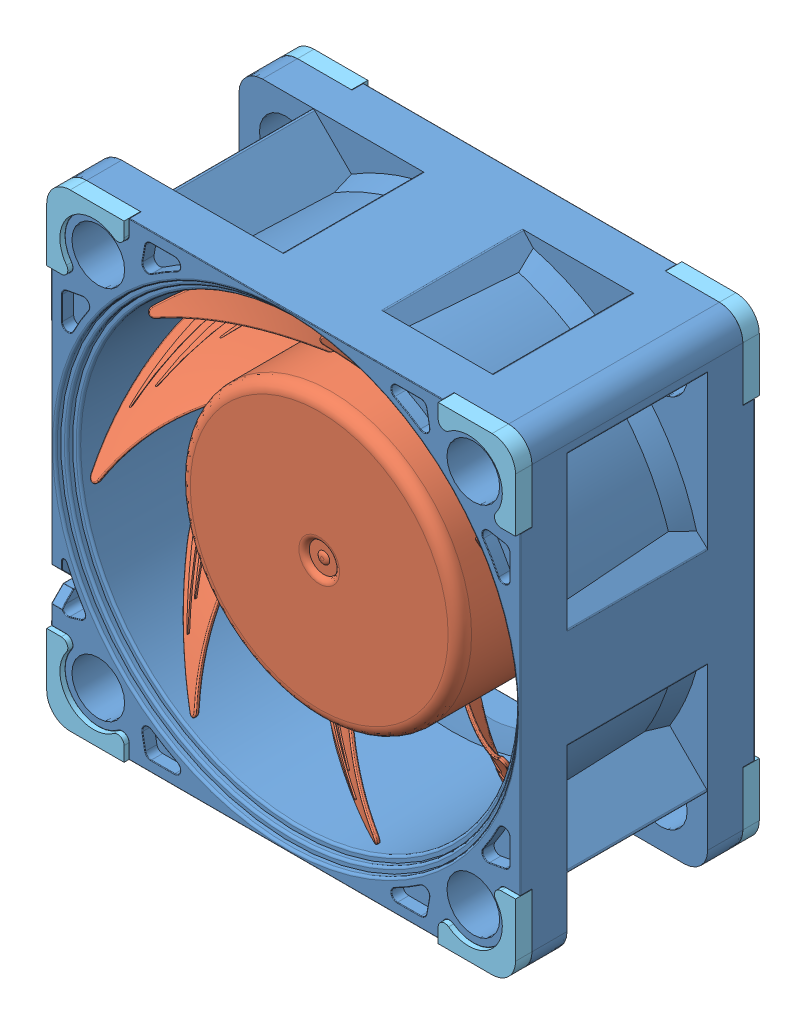
SolidWorks assembly NF-A4x20, configuration Predeterminado. Lengths in mm.
Overall size (49.24 49.24 20.8).
33 component instances, 18 part files, 22 mates.
Components (placement in the parent):
- Case20-1: Case20 [Predeterminado] at origin size (40 40 20.31)
- Impeller20-1: Impeller20 [Predeterminado] at (0 0 5.65) x (-0.910833 -0.412774 0) z (0 0 1) size (37.2 37.2 13.1)
- Magnet 20-1: Magnet 20 [Predeterminado] at (0 0 0.35) size (2 2 1.8)
- Back plate 20-1: Back plate 20 [Predeterminado] at (0 0 -0.05) size (19.4 19.4 0.4)
- Silent block-1: Silent block [Predeterminado] at (-16 16 -0.4) size (6.6 6.6 1.4)
- Silent block-2: Silent block [Predeterminado] at (-16 16 19) size (6.6 6.6 1.4)
- Silent block-3: Silent block [Predeterminado] at (16 16 -0.4) x (0 -1 0) z (0 0 1) size (6.6 6.6 1.4)
- Silent block-4: Silent block [Predeterminado] at (16 -16 -0.4) x (-1 0 0) z (0 0 1) size (6.6 6.6 1.4)
- Silent block-5: Silent block [Predeterminado] at (-16 -16 -0.4) x (0 1 0) z (0 0 1) size (6.6 6.6 1.4)
- Silent block-6: Silent block [Predeterminado] at (16 16 19) x (0 -1 0) z (0 0 1) size (6.6 6.6 1.4)
- Silent block-7: Silent block [Predeterminado] at (16 -16 19) x (-1 0 0) z (0 0 1) size (6.6 6.6 1.4)
- Silent block-8: Silent block [Predeterminado] at (-16 -16 19) x (0 1 0) z (0 0 1) size (6.6 6.6 1.4)
- Brushless motor-1: Brushless motor [Predeterminado] at (0 0 4) x (0.568712 -0.822537 0) z (0 0 1) size (16 16 8.48)
  - Board-1: Board [Predeterminado] at origin size (16 16 0.8)
  - Stator-1: Stator [Predeterminado] at (0 0 3.55) size (11.93 12 5.5)
  - Hall Effect sensor-1: Hall Effect sensor [WE] at (-5.3023 -0.9391 0) x (-0.233503 0.972356 0) z (-0.972356 -0.233503 0) size (6.3 1.6 2.6)
  - Controller-1: Controller [Predeterminado] at (5.1574 2.3195 0) x (0.319288 -0.947658 0) z (0.947658 0.319288 0) size (4.81 0.99 3)
  - Coil-1: Coil [Predeterminado] at (0 -5.01 1.29) x (-1 0 0) z (0 1 0) size (2.38 5.38 1.58)
  - Coil-2: Coil [Predeterminado] at (-4.3388 -2.505 1.29) x (-0.5 0.866025 0) z (0.866025 0.5 0) size (2.38 5.38 1.58)
  - Coil-3: Coil [Predeterminado] at (-4.3388 2.505 1.29) x (0.5 0.866025 0) z (0.866025 -0.5 0) size (2.38 5.38 1.58)
  - Coil-4: Coil [Predeterminado] at (0 5.01 1.29) x (1 0 0) z (0 -1 0) size (2.38 5.38 1.58)
  - Coil-5: Coil [Predeterminado] at (4.3388 2.505 1.29) x (0.5 -0.866025 0) z (-0.866025 -0.5 0) size (2.38 5.38 1.58)
  - Coil-6: Coil [Predeterminado] at (4.3388 -2.505 1.29) x (-0.5 -0.866025 0) z (-0.866025 0.5 0) size (2.38 5.38 1.58)
  - Pieza2^Brushless motor-1: Pieza2^Brushless motor [Predeterminado] at origin size (10.72 12.51 6.88) (virtual)
  - Pieza3^Brushless motor-1: Pieza3^Brushless motor [Predeterminado] at (0 0 0.8) size (4.1 0.74 1.7) (virtual)
- Shaft-1: Shaft [Predeterminado] at (0 0 16.35) x (0.952278 -0.305233 0) z (0 0 1) size (2.38 2.38 12.5)
- Oil Bearing-1: Oil Bearing [Predeterminado] at (0 0 4) x (0.568712 -0.822537 0) z (0 0 -1) size (5 5 5)
  - Bearing-1: Bearing [Predeterminado] at origin size (5 5 5)
  - Bearing gasket-1: Bearing gasket [Predeterminado] at (0 0 -1.3) size (2 2 0.5)
  - Oil-1: Oil [Predeterminado] at (0 0 -4.5) size (4 4 2.7)
  - Bearing gasket-2: Bearing gasket [Predeterminado] at (0 0 -4.5) size (2 2 0.5)
- Rotor-1: Rotor [Predeterminado] at (0 0 5.65) x (0.792012 -0.610506 0) z (0 0 -1) size (16.45 16.45 6.1)
- Magnetic screen-1: Magnetic screen [Predeterminado] at (0 0 5.65) size (16.85 16.85 6)
Mates (geometry in assembly coordinates):
- Coincidente1: coincident aligned: plane of Case20-1 through (0 0 0) normal (0 0 1)
- Coincidente2: coincident aligned: plane of Case20-1 through (0 0 0) normal (0 1 0)
- Coincidente3: coincident aligned: plane of Case20-1 through (0 0 0) normal (1 0 0)
- Concéntrica1: concentric aligned: cylinder of Case20-1 through (0 0 2) axis (0 0 -1) radius 12; cylinder of Impeller20-1 through (0 0 17.15) axis (0 0 -1) radius 12
- Distancia1: distance = 2.85 mm aligned: plane of Impeller20-1 through (0 0 17.15) normal (0 0 1); plane of Case20-1 through (-18.7563 13.9563 20) normal (0 0 1)
- Coincidente4: coincident anti-aligned: plane of Case20-1 through (0 0 2.15) normal (0 0 -1); plane of Magnet-1 through (0 0 2.15) normal (0 0 1)
- Concéntrica2: concentric aligned: cylinder of Case20-1 through (0 0 2.15) axis (0 0 -1) radius 1; cylinder of Magnet-1 through (0 0 2.15) axis (0 0 -1) radius 1
- Concéntrica3: concentric aligned: cylinder of Case20-1 through (0 0 0.35) axis (0 0 -1) radius 9.95; cylinder of Back plate-1 through (0 0 0.35) axis (0 0 -1) radius 9.7
- Coincidente5: coincident anti-aligned: plane of Case20-1 through (0 0 0.35) normal (0 0 -1); plane of Back plate-1 through (0 0 0.35) normal (0 0 1)
- Coincidente6: coincident anti-aligned: plane of Case20-1 through (-18 18 1) normal (0 0 -1); plane of Silent block-1 through (-18.7563 13.9563 1) normal (0 0 1)
- Coincidente7: coincident anti-aligned: plane of Case20-1 through (-13.4 0 1) normal (-1 0 0); plane of Silent block-1 through (-13.4 20 1) normal (1 0 0)
- Coincidente8: coincident anti-aligned: plane of Case20-1 through (0 13.4 1) normal (0 1 0); plane of Silent block-1 through (-20 13.4 1) normal (0 -1 0)
- Concéntrica4: concentric aligned: cylinder of Case20-1 through (0 0 2) axis (0 0 -1) radius 12; cylinder of Brushless motor-1/Board-1 through (0 0 4.8) axis (0 0 -1) radius 8
- Concéntrica5: concentric aligned: circle of Impeller20-1; circle of Shaft-1
- Coincidente9: coincident anti-aligned: plane of Impeller20-1 through (0 0 16.35) normal (0 0 -1); plane of Shaft-1 through (0 0 16.35) normal (0 0 1)
- Concéntrica6: concentric aligned: cylinder of Brushless motor-1/Stator-1 through (0 0 10.3) axis (0 0 -1) radius 2.5; cylinder of Oil Bearing-1/Bearing-1 through (0 0 4) axis (0 0 -1) radius 2.5
- Coincidente10: coincident aligned: plane of Brushless motor-1/Board-1 through (0 0 4) normal (0 0 -1); plane of Oil Bearing-1/Bearing-1 through (-0.8531 1.2338 4) normal (0 0 -1)
- Distancia2: distance = 1.5 mm anti-aligned: plane of Case20-1 through (0 0 2.5) normal (0 0 1); plane of Brushless motor-1/Board-1 through (0 0 4) normal (0 0 -1)
- Concéntrica7: concentric aligned: cylinder of Impeller20-1 through (0 0 17.152) axis (0 0 -1) radius 8.425; cylinder of Rotor-1 through (0 0 11.75) axis (0 0 -1) radius 8.225
- Coincidente11: coincident aligned: plane of Impeller20-1 through (0 0 5.65) normal (0 0 -1); plane of Rotor-1 through (0 0 5.65) normal (0 0 -1)
- Coincidente12: coincident aligned: plane of Impeller20-1 through (0 0 5.65) normal (0 0 -1); plane of Magnetic screen-1 through (0 0 5.65) normal (0 0 -1)
- Concéntrica8: concentric aligned: cylinder of Rotor-1 through (0 0 11.75) axis (0 0 -1) radius 8.225; cylinder of Magnetic screen-1 through (0 0 11.65) axis (0 0 -1) radius 8.425
